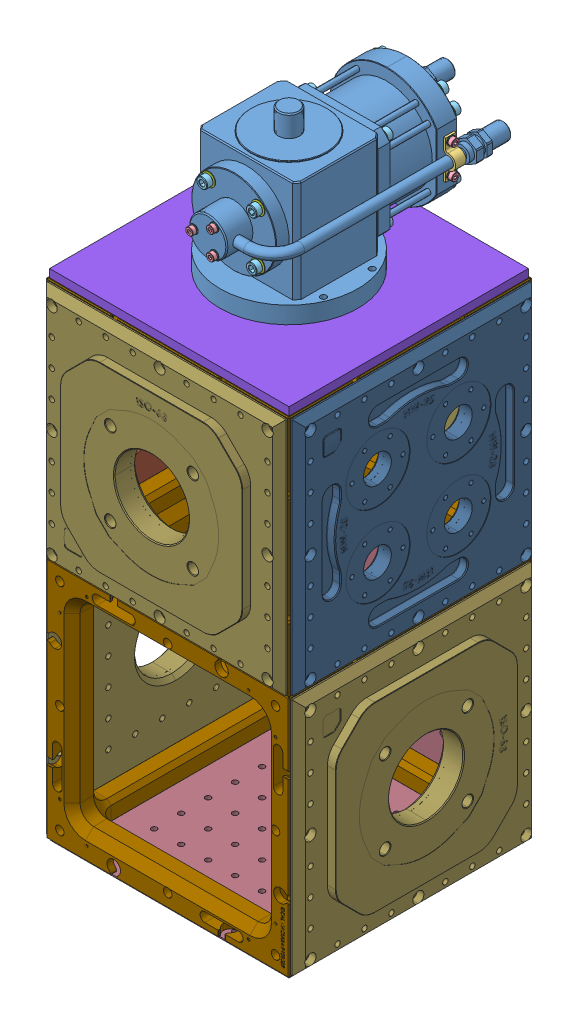
SolidWorks assembly Assem1, configuration Default. Lengths in mm.
Overall size (264.29 605.44 281.94).
89 component instances, 15 part files, 34 mates.
Components (placement in the parent):
- SRDK-101D-1: SRDK-101D [Default] at (-81.6435 -396.7849 -132.244) size (130 442 230.94)
  - SRDK-101D-01-1: SRDK-101D-01 [Default] at (0 517.452 187.325) size (130 133.2 226.3)
  - SRDK-101D-02-1: SRDK-101D-02 [Default] at (0 517.452 187.325) size (81.34 308.8 81.03)
  - SRDK-101D-03-1: SRDK-101D-03 [Default] at (52 581.652 84.425) size (12.07 36 10)
  - HARDWARE_1-1: HARDWARE_1 [Default] at (-13 581.652 256.425) x (0.923728 0.383049 0) z (0 0 -1) size (7 7 12.04)
  - HARDWARE_1-2: HARDWARE_1 [Default] at (42.1 595.652 84.425) x (0 0 1) z (-1 0 0) size (7 7 12.04)
  - HARDWARE_1-3: HARDWARE_1 [Default] at (-9.5459 616.1979 80.925) size (7 7 12.04)
  - HARDWARE_1-4: HARDWARE_1 [Default] at (-11.5 565.752 81.275) size (7 7 12.04)
  - HARDWARE_2-1: HARDWARE_2 [Default] at (-22.2739 623.502 209.5989) x (1 0 0) z (0 -1 0) size (10 10 14.07) (hidden)
  - HARDWARE_2-2: HARDWARE_2 [Default] at (-27.8095 620.7753 82.975) size (10 10 14.07)
  - HARDWARE_2-3: HARDWARE_2 [Default] at (-23.3345 604.9865 232.175) x (0.923728 0.383049 0) z (0 0 -1) size (10 10 14.07)
  - HARDWARE_2-4: HARDWARE_2 [Default] at (-35.3553 617.0073 142.975) x (0.328464 0.944516 0) z (0 0 1) size (10 10 14.07)
  - HARDWARE_3-1: HARDWARE_3 [Default] at (-38.5 618.552 209.825) x (1 0 0) z (0 -1 0) size (13 13 20.09) (hidden)
  - HARDWARE_4-1: HARDWARE_4 [Default] at (-13 581.652 263.825) x (-0.923728 -0.383049 0) z (-0.383049 0.923728 0) size (8 0.6 8)
  - HARDWARE_4-2: HARDWARE_4 [Default] at (-11.5 565.752 73.875) x (1 0 0) z (0 1 0) size (8 0.6 8)
  - HARDWARE_4-3: HARDWARE_4 [Default] at (-9.5459 616.1979 73.525) x (1 0 0) z (0 1 0) size (8 0.6 8)
  - HARDWARE_4-4: HARDWARE_4 [Default] at (49.5 595.652 84.425) x (0 0 1) z (0 1 0) size (8 0.6 8)
  - HARDWARE_5-1: HARDWARE_5 [Default] at (-23.3345 604.9865 239.325) x (-0.923728 -0.383049 0) z (-0.383049 0.923728 0) size (12.5 0.85 12.5)
  - HARDWARE_5-2: HARDWARE_5 [Default] at (-35.3553 617.0073 135.825) x (1 0 0) z (0 1 0) size (12.5 0.85 12.5)
  - HARDWARE_5-3: HARDWARE_5 [Default] at (-22.2739 630.652 209.5989) size (12.5 0.85 12.5) (hidden)
  - HARDWARE_5-4: HARDWARE_5 [Default] at (-27.8095 620.7753 75.825) x (1 0 0) z (0 1 0) size (12.5 0.85 12.5)
  - HARDWARE_6-1: HARDWARE_6 [Default] at (-38.5 629.652 209.825) size (16 0.9 16) (hidden)
  - HARDWARE_1-5: HARDWARE_1 [Default] at (6.5 570.3937 256.425) x (-0.793594 0.608447 0) z (0 0 -1) size (7 7 12.04)
  - HARDWARE_1-6: HARDWARE_1 [Default] at (6.5 592.9103 256.425) x (-0.130134 -0.991496 0) z (0 0 -1) size (7 7 12.04)
  - HARDWARE_4-5: HARDWARE_4 [Default] at (6.5 570.3937 263.825) x (0.793594 -0.608447 0) z (-0.608447 -0.793594 0) size (8 0.6 8)
  - HARDWARE_4-6: HARDWARE_4 [Default] at (6.5 592.9103 263.825) x (0.130134 0.991496 0) z (0.991496 -0.130134 0) size (8 0.6 8)
  - HARDWARE_2-5: HARDWARE_2 [Default] at (-23.3345 558.3175 232.175) x (-0.383049 0.923728 0) z (0 0 -1) size (10 10 14.07)
  - HARDWARE_2-6: HARDWARE_2 [Default] at (23.3345 558.3175 232.175) x (-0.923728 -0.383049 0) z (0 0 -1) size (10 10 14.07)
  - HARDWARE_2-7: HARDWARE_2 [Default] at (23.3345 604.9865 232.175) x (0.383049 -0.923728 0) z (0 0 -1) size (10 10 14.07)
  - HARDWARE_5-5: HARDWARE_5 [Default] at (-23.3345 558.3175 239.325) x (0.383049 -0.923728 0) z (-0.923728 -0.383049 0) size (12.5 0.85 12.5)
  - HARDWARE_5-6: HARDWARE_5 [Default] at (23.3345 558.3175 239.325) x (0.923728 0.383049 0) z (0.383049 -0.923728 0) size (12.5 0.85 12.5)
  - HARDWARE_5-7: HARDWARE_5 [Default] at (23.3345 604.9865 239.325) x (-0.383049 0.923728 0) z (0.923728 0.383049 0) size (12.5 0.85 12.5)
  - HARDWARE_5-8: HARDWARE_5 [Default] at (22.2739 630.652 209.5989) x (0 0 -1) z (1 0 0) size (12.5 0.85 12.5) (hidden)
  - HARDWARE_5-9: HARDWARE_5 [Default] at (22.2739 630.652 165.0511) x (-1 0 0) z (0 0 -1) size (12.5 0.85 12.5) (hidden)
  - HARDWARE_5-10: HARDWARE_5 [Default] at (-22.2739 630.652 165.0511) x (0 0 1) z (-1 0 0) size (12.5 0.85 12.5) (hidden)
  - HARDWARE_2-8: HARDWARE_2 [Default] at (22.2739 623.502 209.5989) x (0 0 -1) z (0 -1 0) size (10 10 14.07) (hidden)
  - HARDWARE_2-9: HARDWARE_2 [Default] at (22.2739 623.502 165.0511) x (-1 0 0) z (0 -1 0) size (10 10 14.07) (hidden)
  - HARDWARE_2-10: HARDWARE_2 [Default] at (-22.2739 623.502 165.0511) x (0 0 1) z (0 -1 0) size (10 10 14.07) (hidden)
  - HARDWARE_6-2: HARDWARE_6 [Default] at (38.5 629.652 209.825) size (16 0.9 16) (hidden)
  - HARDWARE_6-3: HARDWARE_6 [Default] at (-38.5 629.652 159.825) size (16 0.9 16) (hidden)
  - HARDWARE_6-4: HARDWARE_6 [Default] at (38.5 629.652 159.825) size (16 0.9 16) (hidden)
  - HARDWARE_3-2: HARDWARE_3 [Default] at (38.5 618.552 209.825) x (1 0 0) z (0 -1 0) size (13 13 20.09) (hidden)
  - HARDWARE_3-3: HARDWARE_3 [Default] at (-38.5 618.552 159.825) x (1 0 0) z (0 -1 0) size (13 13 20.09) (hidden)
  - HARDWARE_3-4: HARDWARE_3 [Default] at (38.5 618.552 159.825) x (1 0 0) z (0 -1 0) size (13 13 20.09) (hidden)
  - HARDWARE_4-7: HARDWARE_4 [Default] at (9.5459 616.1979 73.525) x (0 -1 0) z (1 0 0) size (8 0.6 8)
  - HARDWARE_4-8: HARDWARE_4 [Default] at (9.5459 597.1061 73.525) x (-1 0 0) z (0 -1 0) size (8 0.6 8)
  - HARDWARE_4-9: HARDWARE_4 [Default] at (-9.5459 597.1061 73.525) x (0 1 0) z (-1 0 0) size (8 0.6 8)
  - HARDWARE_1-7: HARDWARE_1 [Default] at (9.5459 616.1979 80.925) x (0 -1 0) z (0 0 1) size (7 7 12.04)
  - HARDWARE_1-8: HARDWARE_1 [Default] at (9.5459 597.1061 80.925) x (-1 0 0) z (0 0 1) size (7 7 12.04)
  - HARDWARE_1-9: HARDWARE_1 [Default] at (-9.5459 597.1061 80.925) x (0 1 0) z (0 0 1) size (7 7 12.04)
  - HARDWARE_4-10: HARDWARE_4 [Default] at (11.5 565.752 73.875) x (0 -1 0) z (1 0 0) size (8 0.6 8)
  - HARDWARE_4-11: HARDWARE_4 [Default] at (11.5 542.752 73.875) x (-1 0 0) z (0 -1 0) size (8 0.6 8)
  - HARDWARE_4-12: HARDWARE_4 [Default] at (-11.5 542.752 73.875) x (0 1 0) z (-1 0 0) size (8 0.6 8)
  - HARDWARE_1-10: HARDWARE_1 [Default] at (11.5 565.752 81.275) x (0 -1 0) z (0 0 1) size (7 7 12.04)
  - HARDWARE_1-11: HARDWARE_1 [Default] at (11.5 542.752 81.275) x (-1 0 0) z (0 0 1) size (7 7 12.04)
  - HARDWARE_1-12: HARDWARE_1 [Default] at (-11.5 542.752 81.275) x (0 1 0) z (0 0 1) size (7 7 12.04)
  - HARDWARE_5-11: HARDWARE_5 [Default] at (-35.3553 546.2967 135.825) x (0 1 0) z (-1 0 0) size (12.5 0.85 12.5)
  - HARDWARE_5-12: HARDWARE_5 [Default] at (35.3553 546.2967 135.825) x (-1 0 0) z (0 -1 0) size (12.5 0.85 12.5)
  - HARDWARE_5-13: HARDWARE_5 [Default] at (35.3553 617.0073 135.825) x (0 -1 0) z (1 0 0) size (12.5 0.85 12.5)
  - HARDWARE_2-11: HARDWARE_2 [Default] at (-35.3553 546.2967 142.975) x (-0.944516 0.328464 0) z (0 0 1) size (10 10 14.07)
  - HARDWARE_2-12: HARDWARE_2 [Default] at (35.3553 546.2967 142.975) x (-0.328464 -0.944516 0) z (0 0 1) size (10 10 14.07)
  - HARDWARE_2-13: HARDWARE_2 [Default] at (35.3553 617.0073 142.975) x (0.944516 -0.328464 0) z (0 0 1) size (10 10 14.07)
  - HARDWARE_4-13: HARDWARE_4 [Default] at (49.5 567.652 84.425) x (0 0 1) z (0 1 0) size (8 0.6 8)
  - HARDWARE_1-13: HARDWARE_1 [Default] at (42.1 567.652 84.425) x (0 0 1) z (-1 0 0) size (7 7 12.04)
  - HARDWARE_5-14: HARDWARE_5 [Default] at (39.1233 609.4615 75.825) x (0 -1 0) z (1 0 0) size (12.5 0.85 12.5)
  - HARDWARE_5-15: HARDWARE_5 [Default] at (27.8095 542.5287 75.825) x (-1 0 0) z (0 -1 0) size (12.5 0.85 12.5)
  - HARDWARE_5-16: HARDWARE_5 [Default] at (-39.1233 553.8425 75.825) x (0 1 0) z (-1 0 0) size (12.5 0.85 12.5)
  - HARDWARE_2-14: HARDWARE_2 [Default] at (39.1233 609.4615 82.975) x (0 -1 0) z (0 0 1) size (10 10 14.07)
  - HARDWARE_2-15: HARDWARE_2 [Default] at (27.8095 542.5287 82.975) x (-1 0 0) z (0 0 1) size (10 10 14.07)
  - HARDWARE_2-16: HARDWARE_2 [Default] at (-39.1233 553.8425 82.975) x (0 1 0) z (0 0 1) size (10 10 14.07)
  - HARDWARE_5-17: HARDWARE_5 [Default] at (-39.1533 609.4193 75.825) x (0.944089 0.329691 0) z (-0.329691 0.944089 0) size (12.5 0.85 12.5)
  - HARDWARE_2-17: HARDWARE_2 [Default] at (-39.1533 609.4193 82.975) x (0.944089 0.329691 0) z (0 0 1) size (10 10 14.07)
  - HARDWARE_5-18: HARDWARE_5 [Default] at (27.7673 620.8053 75.825) x (0.329691 -0.944089 0) z (0.944089 0.329691 0) size (12.5 0.85 12.5)
  - HARDWARE_5-19: HARDWARE_5 [Default] at (39.1533 553.8847 75.825) x (-0.944089 -0.329691 0) z (0.329691 -0.944089 0) size (12.5 0.85 12.5)
  - HARDWARE_5-20: HARDWARE_5 [Default] at (-27.7673 542.4987 75.825) x (-0.329691 0.944089 0) z (-0.944089 -0.329691 0) size (12.5 0.85 12.5)
  - HARDWARE_2-18: HARDWARE_2 [Default] at (27.7673 620.8053 82.975) x (0.329691 -0.944089 0) z (0 0 1) size (10 10 14.07)
  - HARDWARE_2-19: HARDWARE_2 [Default] at (39.1533 553.8847 82.975) x (-0.944089 -0.329691 0) z (0 0 1) size (10 10 14.07)
  - HARDWARE_2-20: HARDWARE_2 [Default] at (-27.7673 542.4987 82.975) x (-0.329691 0.944089 0) z (0 0 1) size (10 10 14.07)
- Test_Oring-1: Test_Oring [Default] at (-81.6435 113.2471 55.081) size (225.55 7.62 225.55)
- P109589_9x9x9 Frame-1: P109589_9x9x9 Frame [Default] at (-81.6435 -1.0529 55.081) size (229.62 229.62 229.62)
- P109598_4x_KF25-1: P109598_4x_KF25 [Default] at (32.6565 -1.0529 55.081) x (0 -1 0) z (1 0 0) size (225.56 230.1 32.87)
- P1010939_4x_KF40-1: P1010939_4x_KF40 [Default] at (-195.9435 -1.0529 55.081) x (0 0 1) z (-1 0 0) size (225.56 225.56 24.66)
- P109599_9x9_ISO-63-1: P109599_9x9_ISO-63 [Default] at (-81.6435 -1.0529 169.381) size (225.56 227.57 25.53)
- P109599_9x9_ISO-63-2: P109599_9x9_ISO-63 [Default] at (-81.6435 -1.0529 -59.219) x (-1 0 0) z (0 0 -1) size (225.56 227.57 25.53)
- P109589_9x9x9 Frame-2: P109589_9x9x9 Frame [Default] at (-81.6435 -229.6529 55.081) size (229.62 229.62 229.62)
- P109590_9x9_BlankPlate_Painted-1: P109590_9x9_BlankPlate_Painted [Default] at (-81.6435 -229.6529 -59.219) x (-1 0 0) z (0 0 -1) size (225.55 225.55 15.24)
- P109590_9x9_BlankPlate_Painted-2: P109590_9x9_BlankPlate_Painted [Default] at (-81.6435 -343.9529 55.081) x (1 0 0) z (0 -1 0) size (225.55 225.55 15.24)
- P109599_9x9_ISO-63-3: P109599_9x9_ISO-63 [Default] at (-195.9435 -229.6529 55.081) x (0 1 0) z (-1 0 0) size (225.56 227.57 25.53)
- P109599_9x9_ISO-63-4: P109599_9x9_ISO-63 [Default] at (32.6565 -229.6529 55.081) x (0 -1 0) z (1 0 0) size (225.56 227.57 25.53)
Mates (geometry in assembly coordinates):
- Concentric1: concentric aligned: cylinder of SRDK-101D-1/SRDK-101D-01-1 through (-81.6435 136.8671 55.081) axis (0 -1 0) radius 65; cylinder of Test_Oring-1 through (-81.6435 120.8671 55.081) axis (0 -1 0) radius 40
- Concentric2: concentric anti-aligned: circle of SRDK-101D-1/SRDK-101D-01-1; cylinder of Test_Oring-1 through (-26.2108 120.8671 78.042) axis (0 1 0) radius 2.1
- Concentric3: concentric aligned: cylinder of SRDK-101D-1/SRDK-101D-01-1 through (-26.2108 120.8671 32.12) axis (0 1 0) radius 2.75; circle of Test_Oring-1
- Coincident2: coincident anti-aligned: plane of SRDK-101D-1/SRDK-101D-01-1 through (-147.4235 120.8671 120.861) normal (0 -1 0); plane of Test_Oring-1 through (-81.6435 120.8671 55.081) normal (0 1 0)
- Coincident3: coincident anti-aligned: plane of Test_Oring-1 through (-81.6435 113.2471 55.081) normal (0 -1 0); plane of P109589_9x9x9 Frame-1 through (-195.9435 113.2471 169.381) normal (0 1 0)
- Distance1: distance = 1.524 mm aligned: plane of P109589_9x9x9 Frame-1 through (-81.6435 -1.0529 -59.219) normal (0 0 -1); plane of Test_Oring-1 through (-81.6435 120.8671 -57.695) normal (0 0 -1)
- Distance3: distance = 1.524 mm aligned: plane of Test_Oring-1 through (-194.4195 120.8671 55.081) normal (-1 0 0); plane of P109589_9x9x9 Frame-1 through (-195.9435 113.2471 169.381) normal (-1 0 0)
- Coincident7: coincident anti-aligned: plane of P109589_9x9x9 Frame-1 through (-195.9435 -115.3529 169.381) normal (0 -1 0); plane of P109589_9x9x9 Frame-2 through (-195.9435 -115.3529 169.381) normal (0 1 0)
- Coincident8: coincident aligned: plane of P109589_9x9x9 Frame-1 through (-81.6435 -1.0529 169.381) normal (0 0 1); plane of P109589_9x9x9 Frame-2 through (-81.6435 -229.6529 169.381) normal (0 0 1)
- Coincident9: coincident aligned: plane of P109589_9x9x9 Frame-1 through (32.6565 113.2471 169.381) normal (1 0 0); plane of P109589_9x9x9 Frame-2 through (32.6565 -115.3529 169.381) normal (1 0 0)
- Coincident10: coincident aligned: plane of P109589_9x9x9 Frame-1 through (32.6565 113.2471 169.381) normal (1 0 0); plane of P109598_4x_KF25-1 through (32.6565 -1.0529 55.081) normal (1 0 0)
- Concentric4: concentric aligned: circle of P109589_9x9x9 Frame-1; cylinder of P109598_4x_KF25-1 through (40.2765 100.5471 156.681) axis (1 0 0) radius 3.3782
- Concentric5: concentric aligned: cylinder of P109589_9x9x9 Frame-1 through (32.6565 -102.6529 -46.519) axis (1 0 0) radius 4.0475; cylinder of P109598_4x_KF25-1 through (40.2765 -102.6529 -46.519) axis (1 0 0) radius 3.3782
- Coincident14: coincident aligned: plane of P109589_9x9x9 Frame-1 through (-195.9435 113.2471 169.381) normal (-1 0 0); plane of P1010939_4x_KF40-1 through (-195.9435 -1.0529 55.081) normal (-1 0 0)
- Concentric7: concentric aligned: cylinder of P109589_9x9x9 Frame-1 through (-195.9435 100.5471 -46.519) axis (-1 0 0) radius 4.0475; cylinder of P1010939_4x_KF40-1 through (-203.5635 100.5471 -46.519) axis (-1 0 0) radius 5.1943
- Concentric8: concentric aligned: cylinder of P109589_9x9x9 Frame-1 through (-195.9435 -102.6529 -46.519) axis (-1 0 0) radius 4.0475; cylinder of P1010939_4x_KF40-1 through (-203.5635 -102.6529 -46.519) axis (-1 0 0) radius 5.1943
- Coincident17: coincident anti-aligned: plane of P109589_9x9x9 Frame-2 through (-195.9435 -343.9529 169.381) normal (0 -1 0); plane of P109590_9x9_BlankPlate_Painted-2 through (-81.6435 -343.9529 55.081) normal (0 1 0)
- Concentric13: concentric aligned: cylinder of P109589_9x9x9 Frame-2 through (19.9565 -343.9529 156.681) axis (0 -1 0) radius 4.0475; cylinder of P109590_9x9_BlankPlate_Painted-2 through (19.9565 -351.5729 156.681) axis (0 -1 0) radius 5.1943
- Concentric14: concentric aligned: cylinder of P109589_9x9x9 Frame-2 through (19.9565 -343.9529 -46.519) axis (0 -1 0) radius 4.0475; cylinder of P109590_9x9_BlankPlate_Painted-2 through (19.9565 -351.5729 -46.519) axis (0 -1 0) radius 5.1943
- Coincident18: coincident aligned: plane of P109589_9x9x9 Frame-1 through (-81.6435 -1.0529 169.381) normal (0 0 1); plane of P109599_9x9_ISO-63-1 through (-81.6435 -1.0529 169.381) normal (0 0 1)
- Concentric15: concentric aligned: cylinder of P109589_9x9x9 Frame-1 through (-183.2435 100.5471 169.381) axis (0 0 1) radius 4.0475; cylinder of P109599_9x9_ISO-63-1 through (-183.2435 100.5471 177.001) axis (0 0 1) radius 5.1943
- Concentric16: concentric aligned: cylinder of P109589_9x9x9 Frame-1 through (19.9565 100.5471 169.381) axis (0 0 1) radius 4.0475; cylinder of P109599_9x9_ISO-63-1 through (19.9565 100.5471 177.001) axis (0 0 1) radius 5.1943
- Coincident19: coincident aligned: plane of P109589_9x9x9 Frame-1 through (-81.6435 -1.0529 -59.219) normal (0 0 -1); plane of P109599_9x9_ISO-63-2 through (-81.6435 -1.0529 -59.219) normal (0 0 -1)
- Concentric17: concentric aligned: cylinder of P109589_9x9x9 Frame-1 through (19.9565 100.5471 -59.219) axis (0 0 -1) radius 4.0475; cylinder of P109599_9x9_ISO-63-2 through (19.9565 100.5471 -66.839) axis (0 0 -1) radius 5.1943
- Concentric18: concentric aligned: cylinder of P109589_9x9x9 Frame-1 through (-183.2435 100.5471 -59.219) axis (0 0 -1) radius 4.0475; cylinder of P109599_9x9_ISO-63-2 through (-183.2435 100.5471 -66.839) axis (0 0 -1) radius 5.1943
- Coincident23: coincident: plane of P109589_9x9x9 Frame-2 through (-195.9435 -115.3529 169.381) normal (-1 0 0); plane of P109599_9x9_ISO-63-3 through (-195.9435 -229.6529 55.081) normal (-1 0 0)
- Concentric25: concentric: cylinder of P109589_9x9x9 Frame-2 through (-195.9435 -128.0529 156.681) axis (-1 0 0) radius 4.0475; cylinder of P109599_9x9_ISO-63-3 through (-203.5635 -128.0529 156.681) axis (-1 0 0) radius 5.1943
- Concentric26: concentric aligned: cylinder of P109589_9x9x9 Frame-2 through (-195.9435 -331.2529 156.681) axis (-1 0 0) radius 4.0475; cylinder of P109599_9x9_ISO-63-3 through (-203.5635 -331.2529 156.681) axis (-1 0 0) radius 5.1943
- Coincident24: coincident: plane of P109589_9x9x9 Frame-2 through (32.6565 -115.3529 169.381) normal (1 0 0); plane of P109599_9x9_ISO-63-4 through (32.6565 -229.6529 55.081) normal (1 0 0)
- Concentric27: concentric: cylinder of P109589_9x9x9 Frame-2 through (32.6565 -331.2529 -46.519) axis (1 0 0) radius 4.0475; cylinder of P109599_9x9_ISO-63-4 through (40.2765 -331.2529 -46.519) axis (1 0 0) radius 5.1943
- Concentric28: concentric aligned: cylinder of P109589_9x9x9 Frame-2 through (32.6565 -128.0529 -46.519) axis (1 0 0) radius 4.0475; cylinder of P109599_9x9_ISO-63-4 through (40.2765 -128.0529 -46.519) axis (1 0 0) radius 5.1943
- Coincident25: coincident: plane of P109589_9x9x9 Frame-2 through (-81.6435 -229.6529 -59.219) normal (0 0 -1); plane of P109590_9x9_BlankPlate_Painted-1 through (-81.6435 -229.6529 -59.219) normal (0 0 1)
- Concentric29: concentric: cylinder of P109589_9x9x9 Frame-2 through (19.9565 -128.0529 -59.219) axis (0 0 -1) radius 4.0475; cylinder of P109590_9x9_BlankPlate_Painted-1 through (19.9565 -128.0529 -66.839) axis (0 0 -1) radius 5.1943
- Concentric30: concentric aligned: cylinder of P109589_9x9x9 Frame-2 through (-183.2435 -128.0529 -59.219) axis (0 0 -1) radius 4.0475; cylinder of P109590_9x9_BlankPlate_Painted-1 through (-183.2435 -128.0529 -66.839) axis (0 0 -1) radius 5.1943
